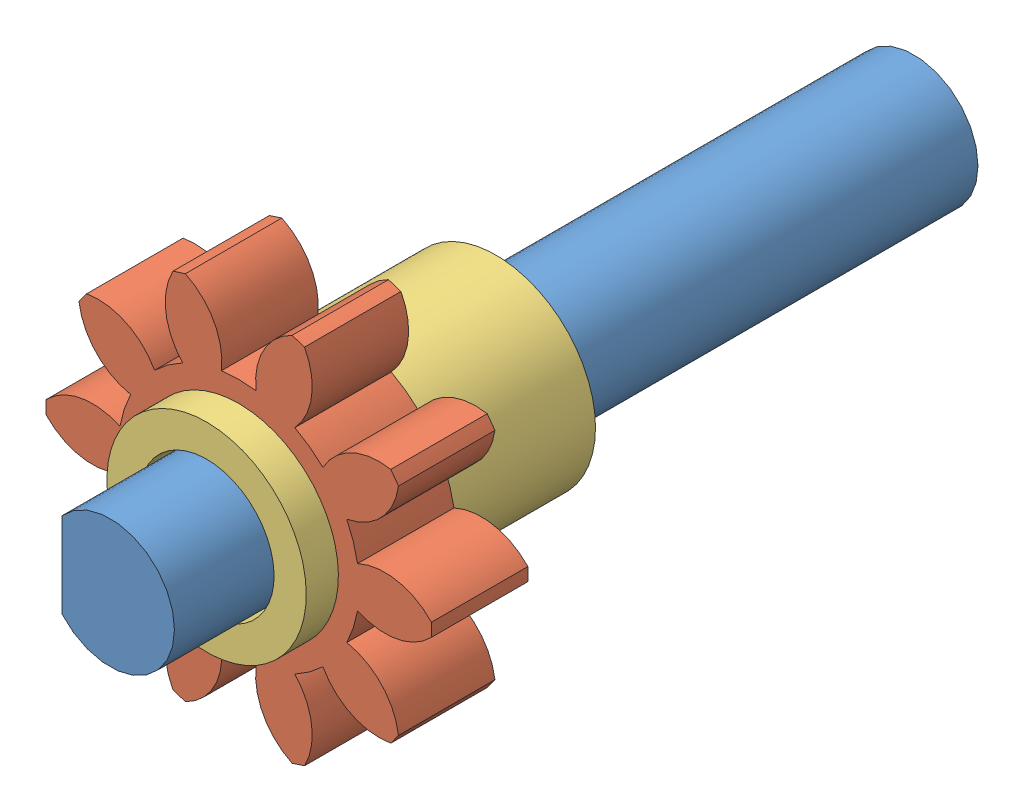
SolidWorks assembly Subassembly 1, configuration Default. Lengths in mm.
Overall size (12 11.53 25).
4 component instances, 3 part files, 7 mates.
Components (placement in the parent):
- axle-1: axle [25mm axle] at (-2.8918 22.5281 -2.0712) size (3.5 4 25)
- root gear assignment-1: root gear assignment [10T 1.0Mod] at (-2.8918 22.5281 18.9288) x (-1 0 0) z (0 0 -1) size (12 11.53 3)
- Spacer-1: Spacer [4.2-1] at (-2.8918 22.5281 18.9288) x (0.950881 0.309557 0) z (0 0 1) size (6.2 6.2 1)
- Spacer-2: Spacer [4.2-5] at (-2.8918 22.5281 10.9288) x (-0.422504 -0.906361 0) z (0 0 1) size (6.2 6.2 5)
Mates (geometry in assembly coordinates):
- Coincident4: coincident anti-aligned: plane of axle-1 through (-4.3918 23.851 22.9288) normal (-1 0 0); plane of root gear assignment-1 through (-4.3918 23.851 15.9288) normal (1 0 0)
- Concentric1: concentric anti-aligned: cylinder of axle-1 through (-2.8918 22.5281 22.9288) axis (0 0 -1) radius 2; cylinder of root gear assignment-1 through (-2.8918 22.5281 15.9288) axis (0 0 1) radius 2
- Concentric2: concentric aligned: cylinder of axle-1 through (-2.8918 22.5281 22.9288) axis (0 0 -1) radius 2; cylinder of Spacer-1 through (-2.8918 22.5281 19.9288) axis (0 0 -1) radius 2.1
- Concentric3: concentric aligned: cylinder of axle-1 through (-2.8918 22.5281 22.9288) axis (0 0 -1) radius 2; cylinder of Spacer-2 through (-2.8918 22.5281 15.9288) axis (0 0 -1) radius 2.1
- Coincident5: coincident anti-aligned: plane of root gear assignment-1 through (-2.8918 22.5281 15.9288) normal (0 0 -1); plane of Spacer-2 through (-2.8918 22.5281 15.9288) normal (0 0 1)
- Coincident6: coincident anti-aligned: plane of root gear assignment-1 through (-2.8918 22.5281 18.9288) normal (0 0 1); plane of Spacer-1 through (-2.8918 22.5281 18.9288) normal (0 0 -1)
- Distance1: distance = 3 mm aligned: plane of Spacer-1 through (-2.8918 22.5281 19.9288) normal (0 0 1); plane of axle-1 through (-2.8918 22.5281 22.9288) normal (0 0 1)
